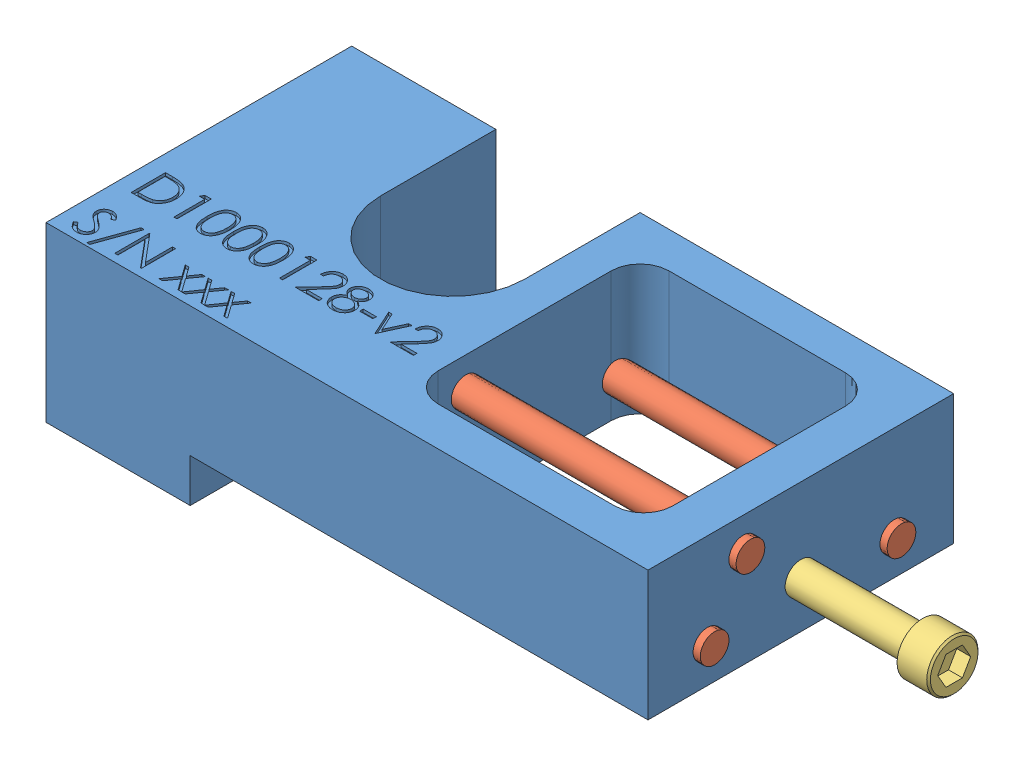
SolidWorks assembly D1001623-v1_aLIGO_ETMITM_PM_prism_holder_assy, configuration Default. Lengths in mm.
Overall size (52.38 12 21.2).
5 component instances, 3 part files, 8 mates.
Components (placement in the parent):
- D1000128-v2_Prism_holder_new_PM-1: D1000128-v2_Prism_holder_new_PM [Default] at (-17.3387 -11.1343 12.2221) size (41.75 12 21.2)
- Prism_holder_pin-1: Prism_holder_pin [Default] at (2.9113 -5.6343 8.1008) x (0 -1 0) z (0 0 1) size (2 22 2)
- Prism_holder_pin-2: Prism_holder_pin [Default] at (2.9113 -1.3343 5.6177) x (0 -1 0) z (0 0 1) size (2 22 2)
- Prism_holder_pin-3: Prism_holder_pin [Default] at (2.9113 -5.6343 -4.8566) x (0 -1 0) z (0 0 1) size (2 22 2)
- Ag-SST_Socketheadcapscrew-2: Ag-SST_Socketheadcapscrew [SHCS #2-56  X 0.5] at (35.0457 -4.8843 1.6221) x (0 0 -1) z (1 0 0) size (3.56 3.56 14.88)
Mates (geometry in assembly coordinates):
- Concentric1: concentric anti-aligned: cylinder of D1000128-v2_Prism_holder_new_PM-1 through (1.4113 -5.6343 8.1008) axis (1 0 0) radius 1; cylinder of Prism_holder_pin-1 through (24.9113 -5.6343 8.1008) axis (-1 0 0) radius 1
- Distance1: distance = 0.5 mm aligned: plane of Prism_holder_pin-1 through (24.9113 -5.6343 8.1008) normal (1 0 0); plane of D1000128-v2_Prism_holder_new_PM-1 through (24.4113 0.8657 12.2221) normal (1 0 0)
- Coincident2: coincident anti-aligned: circle of D1000128-v2_Prism_holder_new_PM-1; cylinder of Prism_holder_pin-2 through (24.9113 -1.3343 5.6177) axis (-1 0 0) radius 1
- Distance2: distance = 0.5 mm aligned: plane of Prism_holder_pin-2 through (24.9113 -1.3343 5.6177) normal (1 0 0); plane of D1000128-v2_Prism_holder_new_PM-1 through (24.4113 0.8657 12.2221) normal (1 0 0)
- Concentric2: concentric anti-aligned: cylinder of D1000128-v2_Prism_holder_new_PM-1 through (1.4113 -5.6343 -4.8566) axis (1 0 0) radius 1; cylinder of Prism_holder_pin-3 through (24.9113 -5.6343 -4.8566) axis (-1 0 0) radius 1
- Distance3: distance = 0.5 mm aligned: plane of Prism_holder_pin-3 through (24.9113 -5.6343 -4.8566) normal (1 0 0); plane of D1000128-v2_Prism_holder_new_PM-1 through (24.4113 0.8657 12.2221) normal (1 0 0)
- Concentric4: concentric aligned: cylinder of Ag-SST_Socketheadcapscrew-2 through (20.1613 -4.8843 1.6221) axis (1 0 0) radius 1.0922; cylinder of D1000128-v2_Prism_holder_new_PM-1 through (19.4113 -4.8843 1.6221) axis (1 0 0) radius 1
- Distance5: distance = 15 mm anti-aligned: plane of Ag-SST_Socketheadcapscrew-2 through (20.1613 -4.8843 1.6221) normal (-1 0 0); plane of D1000128-v2_Prism_holder_new_PM-1 through (5.1613 0.8657 -6.4779) normal (1 0 0)
